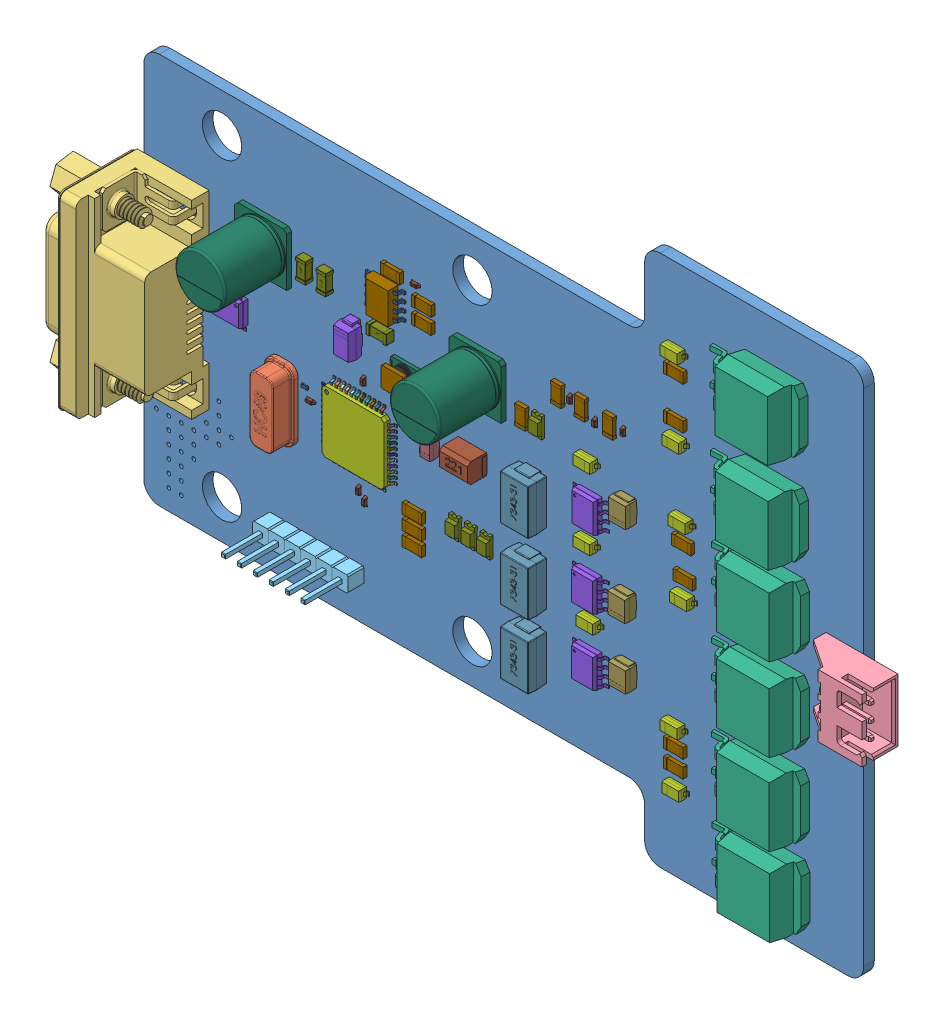
SolidWorks assembly PCB_BLDC421232_СБ, configuration По умолчанию. Lengths in mm.
Overall size (126.59 85 25.25).
246 component instances, 91 part files, 0 mates.
Components (placement in the parent):
- Board-1: Board [По умолчанию] at origin size (115 85 1.69)
- ZQ1-1: ZQ1 [По умолчанию] at origin size (4.65 11.35 16.3)
  - User_Library-HC49_Crystal-1: User_Library-HC49_Crystal [По умолчанию] at (22.338 -6.587 0) x (0 1 0) z (1 0 0) size (11.35 16.3 4.65)
- XS1-1: XS1 [По умолчанию] at origin size (16.7 30.5 16.4)
  - User_Library-DB-9F-1: User_Library-DB-9F [По умолчанию] at (-1.1101 1.395 6.3) x (0 -1 0) z (-1 0 0) size (30.5 16.4 16.7)
- XP2-1: XP2 [По умолчанию] at origin size (11.5 10 9.25)
  - User_Library-DS1069-3_CWF-3R-1: User_Library-DS1069-3_CWF-3R [По умолчанию] at (111.5999 -2.9999 0) x (0 1 0) z (0 0 1) size (10 11.5 9.25)
- XP1-1: XP1 [По умолчанию] at origin size (15.24 2.54 11.54)
  - User_Library-PLS-2-1: User_Library-PLS-2 [По умолчанию] at (19.9299 -25.8001 0) x (1 0 0) z (0 -1 0) size (5.08 11.54 2.54)
  - User_Library-PLS-2-2: User_Library-PLS-2 [По умолчанию] at (25.0099 -25.8001 0) x (1 0 0) z (0 -1 0) size (5.08 11.54 2.54)
  - User_Library-PLS-2-3: User_Library-PLS-2 [По умолчанию] at (30.0899 -25.8001 0) x (1 0 0) z (0 -1 0) size (5.08 11.54 2.54)
- VT6-1: VT6 [По умолчанию] at origin size (15.26 10.16 5.02)
  - SW3dPS-DPAK-1: SW3dPS-DPAK [По умолчанию] at (100.6751 -33.2751 2.5) x (0 -1 0) z (-1 0 0) size (10.16 5.02 15.26)
- VT5-1: VT5 [По умолчанию] at origin size (15.26 10.16 5.02)
  - SW3dPS-DPAK-1: SW3dPS-DPAK [По умолчанию] at (100.5951 -20.7351 2.5) x (0 -1 0) z (-1 0 0) size (10.16 5.02 15.26)
- VT4-1: VT4 [По умолчанию] at origin size (15.26 10.16 5.02)
  - SW3dPS-DPAK-1: SW3dPS-DPAK [По умолчанию] at (100.5951 -7.7351 2.5) x (0 -1 0) z (-1 0 0) size (10.16 5.02 15.26)
- VT3-1: VT3 [По умолчанию] at origin size (15.26 10.16 5.02)
  - SW3dPS-DPAK-1: SW3dPS-DPAK [По умолчанию] at (100.5951 5.5149 2.5) x (0 -1 0) z (-1 0 0) size (10.16 5.02 15.26)
- VT2-1: VT2 [По умолчанию] at origin size (15.26 10.16 5.02)
  - SW3dPS-DPAK-1: SW3dPS-DPAK [По умолчанию] at (100.4251 18.1019 2.5) x (0 -1 0) z (-1 0 0) size (10.16 5.02 15.26)
- VT1-1: VT1 [По умолчанию] at origin size (15.26 10.16 5.02)
  - SW3dPS-DPAK-1: SW3dPS-DPAK [По умолчанию] at (100.3451 32.5619 2.5) x (0 -1 0) z (-1 0 0) size (10.16 5.02 15.26)
- VD10-1: VD10 [По умолчанию] at origin size (3.7 1.6 1.27)
  - SW3DPS-SOD123-DEFAULT-1: SW3DPS-SOD123-DEFAULT [По умолчанию] at (85.3569 -28.75 0) x (-1 0 0) z (0 1 0) size (3.7 1.27 1.6)
- VD9-1: VD9 [По умолчанию] at origin size (3.7 1.6 1.27)
  - SW3DPS-SOD123-DEFAULT-1: SW3DPS-SOD123-DEFAULT [По умолчанию] at (85.1069 -20.25 0) x (-1 0 0) z (0 1 0) size (3.7 1.27 1.6)
- VD8-1: VD8 [По умолчанию] at origin size (3.7 1.6 1.27)
  - SW3DPS-SOD123-DEFAULT-1: SW3DPS-SOD123-DEFAULT [По умолчанию] at (86.6069 -1.75 0) x (-1 0 0) z (0 1 0) size (3.7 1.27 1.6)
- VD7-1: VD7 [По умолчанию] at origin size (3.7 1.6 1.27)
  - SW3DPS-SOD123-DEFAULT-1: SW3DPS-SOD123-DEFAULT [По умолчанию] at (86.3569 8.75 0) x (-1 0 0) z (0 1 0) size (3.7 1.27 1.6)
- VD6-1: VD6 [По умолчанию] at origin size (3.7 1.6 1.27)
  - SW3DPS-SOD123-DEFAULT-1: SW3DPS-SOD123-DEFAULT [По умолчанию] at (85.3649 19.377 0) x (-1 0 0) z (0 1 0) size (3.7 1.27 1.6)
- VD5-1: VD5 [По умолчанию] at origin size (3.7 1.6 1.27)
  - SW3DPS-SOD123-DEFAULT-1: SW3DPS-SOD123-DEFAULT [По умолчанию] at (85.1069 31.6269 0) x (-1 0 0) z (0 1 0) size (3.7 1.27 1.6)
- VD4-1: VD4 [По умолчанию] at origin size (3.7 1.6 1.27)
  - SW3DPS-SOD123-DEFAULT-1: SW3DPS-SOD123-DEFAULT [По умолчанию] at (71.6431 -12.5 0) x (1 0 0) z (0 -1 0) size (3.7 1.27 1.6)
- VD3-1: VD3 [По умолчанию] at origin size (3.7 1.6 1.27)
  - SW3DPS-SOD123-DEFAULT-1: SW3DPS-SOD123-DEFAULT [По умолчанию] at (71.1431 -1.75 0) x (1 0 0) z (0 -1 0) size (3.7 1.27 1.6)
- VD2-1: VD2 [По умолчанию] at origin size (3.7 1.6 1.27)
  - SW3DPS-SOD123-DEFAULT-1: SW3DPS-SOD123-DEFAULT [По умолчанию] at (71.1431 9.5 0) x (1 0 0) z (0 -1 0) size (3.7 1.27 1.6)
- VD1-1: VD1 [По умолчанию] at origin size (2.6 5.21 2.43)
  - SW3dPS-DO-214AC_SMA-1: SW3dPS-DO-214AC_SMA [По умолчанию] at (33.9999 8.2001 1.5) x (1 0 0) z (0 0 1) size (2.6 5.21 2.43)
- R24-1: R24 [По умолчанию] at origin size (1.66 3.1 0.62)
  - ЁхчшёЄюЁ-1206-1: ЁхчшёЄюЁ-1206 [По умолчанию] at (60.7501 10.4999 0.09) x (0 -1 0) z (-1 0 0) size (3.1 0.62 1.66)
- R23-1: R23 [По умолчанию] at origin size (3.1 1.66 0.62)
  - ЁхчшёЄюЁ-1206-1: ЁхчшёЄюЁ-1206 [По умолчанию] at (85.2501 -25.7499 0.09) x (1 0 0) z (0 -1 0) size (3.1 0.62 1.66)
- R22-1: R22 [По умолчанию] at origin size (3.1 1.66 0.62)
  - ЁхчшёЄюЁ-1206-1: ЁхчшёЄюЁ-1206 [По умолчанию] at (85.2501 -22.9999 0.09) x (1 0 0) z (0 -1 0) size (3.1 0.62 1.66)
- R21-1: R21 [По умолчанию] at origin size (3.1 1.66 0.62)
  - ЁхчшёЄюЁ-1206-1: ЁхчшёЄюЁ-1206 [По умолчанию] at (86.7501 1.0001 0.09) x (1 0 0) z (0 -1 0) size (3.1 0.62 1.66)
- R20-1: R20 [По умолчанию] at origin size (3.1 1.66 0.62)
  - ЁхчшёЄюЁ-1206-1: ЁхчшёЄюЁ-1206 [По умолчанию] at (86.5001 5.7501 0.09) x (1 0 0) z (0 -1 0) size (3.1 0.62 1.66)
- R19-1: R19 [По умолчанию] at origin size (3.1 1.66 0.62)
  - ЁхчшёЄюЁ-1206-1: ЁхчшёЄюЁ-1206 [По умолчанию] at (85.2501 22.1271 0.09) x (1 0 0) z (0 -1 0) size (3.1 0.62 1.66)
- R18-1: R18 [По умолчанию] at origin size (3.1 1.66 0.62)
  - ЁхчшёЄюЁ-1206-1: ЁхчшёЄюЁ-1206 [По умолчанию] at (85.2501 28.8771 0.09) x (1 0 0) z (0 -1 0) size (3.1 0.62 1.66)
- R17-1: R17 [По умолчанию] at origin size (1 0.5 0.25)
  - User_Library-d0402h025-1: User_Library-d0402h025 [По умолчанию] at (52.6499 -1.9999 0) x (-1 0 0) z (0 0 1) size (1 0.5 0.25)
- R16-1: R16 [По умолчанию] at origin size (3.1 1.66 0.62)
  - ЁхчшёЄюЁ-1206-1: ЁхчшёЄюЁ-1206 [По умолчанию] at (73.7501 20.9999 -1.7814) x (1 0 0) z (0 1 0) size (3.1 0.62 1.66)
- R15-1: R15 [По умолчанию] at origin size (3.1 1.66 0.62)
  - ЁхчшёЄюЁ-1206-1: ЁхчшёЄюЁ-1206 [По умолчанию] at (73.7501 23.7499 -1.7814) x (1 0 0) z (0 1 0) size (3.1 0.62 1.66)
- R14-1: R14 [По умолчанию] at origin size (3.1 1.66 0.62)
  - ЁхчшёЄюЁ-1206-1: ЁхчшёЄюЁ-1206 [По умолчанию] at (73.7501 26.2499 -1.7814) x (1 0 0) z (0 1 0) size (3.1 0.62 1.66)
- R13-1: R13 [По умолчанию] at origin size (1.66 3.1 0.62)
  - ЁхчшёЄюЁ-1206-1: ЁхчшёЄюЁ-1206 [По умолчанию] at (74.7499 16.2501 0.09) x (0 1 0) z (1 0 0) size (3.1 0.62 1.66)
- R12-1: R12 [По умолчанию] at origin size (1.66 3.1 0.62)
  - ЁхчшёЄюЁ-1206-1: ЁхчшёЄюЁ-1206 [По умолчанию] at (70.2499 16.5001 0.09) x (0 1 0) z (1 0 0) size (3.1 0.62 1.66)
- R11-1: R11 [По умолчанию] at origin size (3.1 1.66 0.62)
  - ЁхчшёЄюЁ-1206-1: ЁхчшёЄюЁ-1206 [По умолчанию] at (67.0001 20.9999 -1.7814) x (1 0 0) z (0 1 0) size (3.1 0.62 1.66)
- R10-1: R10 [По умолчанию] at origin size (3.1 1.66 0.62)
  - ЁхчшёЄюЁ-1206-1: ЁхчшёЄюЁ-1206 [По умолчанию] at (67.0001 23.7499 -1.7814) x (1 0 0) z (0 1 0) size (3.1 0.62 1.66)
- R9-1: R9 [По умолчанию] at origin size (3.1 1.66 0.62)
  - ЁхчшёЄюЁ-1206-1: ЁхчшёЄюЁ-1206 [По умолчанию] at (67.0001 26.2499 -1.7814) x (1 0 0) z (0 1 0) size (3.1 0.62 1.66)
- R8-1: R8 [По умолчанию] at origin size (1.66 3.1 0.62)
  - ЁхчшёЄюЁ-1206-1: ЁхчшёЄюЁ-1206 [По умолчанию] at (66.4999 16.5001 0.09) x (0 1 0) z (1 0 0) size (3.1 0.62 1.66)
- R7-1: R7 [По умолчанию] at origin size (1 0.5 0.25)
  - User_Library-d0402h025-1: User_Library-d0402h025 [По умолчанию] at (25.8501 -3.0001 0) x (1 0 0) z (0 0 1) size (1 0.5 0.25)
- R6-1: R6 [По умолчанию] at origin size (3.1 1.66 0.62)
  - ЁхчшёЄюЁ-1206-1: ЁхчшёЄюЁ-1206 [По умолчанию] at (45.0001 15.5001 0.09) x (1 0 0) z (0 -1 0) size (3.1 0.62 1.66)
- R5-1: R5 [По умолчанию] at origin size (3.1 1.66 0.62)
  - ЁхчшёЄюЁ-1206-1: ЁхчшёЄюЁ-1206 [По умолчанию] at (45.0001 18.0001 0.09) x (1 0 0) z (0 -1 0) size (3.1 0.62 1.66)
- R4-1: R4 [По умолчанию] at origin size (3.1 1.66 0.62)
  - ЁхчшёЄюЁ-1206-1: ЁхчшёЄюЁ-1206 [По умолчанию] at (40.0001 20.0001 0.09) x (1 0 0) z (0 -1 0) size (3.1 0.62 1.66)
- R3-1: R3 [По умолчанию] at origin size (3.1 1.66 0.62)
  - ЁхчшёЄюЁ-1206-1: ЁхчшёЄюЁ-1206 [По умолчанию] at (43.4999 -16.0001 0.09) x (-1 0 0) z (0 1 0) size (3.1 0.62 1.66)
- R2-1: R2 [По умолчанию] at origin size (3.1 1.66 0.62)
  - ЁхчшёЄюЁ-1206-1: ЁхчшёЄюЁ-1206 [По умолчанию] at (43.4999 -11.5001 0.09) x (-1 0 0) z (0 1 0) size (3.1 0.62 1.66)
- R1-1: R1 [По умолчанию] at origin size (3.1 1.66 0.62)
  - ЁхчшёЄюЁ-1206-1: ЁхчшёЄюЁ-1206 [По умолчанию] at (43.4999 -13.7501 0.09) x (-1 0 0) z (0 1 0) size (3.1 0.62 1.66)
- L2-1: L2 [По умолчанию] at origin size (4.65 3.2 3.08)
  - ╚эфєъЄштэюёЄ№NLC453232-1: ╚эфєъЄштэюёЄ№NLC453232 [По умолчанию] at (52.5359 0.699 0.05) x (1 0 0) z (0 -1 0) size (4.65 3.08 3.2)
- L1-1: L1 [По умолчанию] at origin size (4.6 3.2 2.6)
  - User_Library-lqh4c_1812-1: User_Library-lqh4c_1812 [По умолчанию] at (42.25 7 0) x (1 0 0) z (0 0 1) size (4.6 3.2 2.6)
    - User_Library-lqh4c_1812_Torus-1: User_Library-lqh4c_1812_Torus [По умолчанию] at origin size (2.9 2.9 0.1)
    - User_Library-lqh4c_1812_Torus001-1: User_Library-lqh4c_1812_Torus001 [По умолчанию] at origin size (2.9 2.9 0.1)
    - User_Library-lqh4c_1812_Torus002-1: User_Library-lqh4c_1812_Torus002 [По умолчанию] at origin size (2.9 2.9 0.1)
    - User_Library-lqh4c_1812_Torus003-1: User_Library-lqh4c_1812_Torus003 [По умолчанию] at origin size (2.9 2.9 0.1)
    - User_Library-lqh4c_1812_Torus004-1: User_Library-lqh4c_1812_Torus004 [По умолчанию] at origin size (2.9 2.9 0.1)
    - User_Library-lqh4c_1812_Torus005-1: User_Library-lqh4c_1812_Torus005 [По умолчанию] at origin size (2.9 2.9 0.1)
    - User_Library-lqh4c_1812_Torus006-1: User_Library-lqh4c_1812_Torus006 [По умолчанию] at origin size (2.9 2.9 0.1)
    - User_Library-lqh4c_1812_Torus007-1: User_Library-lqh4c_1812_Torus007 [По умолчанию] at origin size (2.9 2.9 0.1)
    - User_Library-lqh4c_1812_Torus008-1: User_Library-lqh4c_1812_Torus008 [По умолчанию] at origin size (2.9 2.9 0.1)
    - User_Library-lqh4c_1812_Torus009-1: User_Library-lqh4c_1812_Torus009 [По умолчанию] at origin size (2.9 2.9 0.1)
    - User_Library-lqh4c_1812_Torus010-1: User_Library-lqh4c_1812_Torus010 [По умолчанию] at origin size (2.9 2.9 0.1)
    - User_Library-lqh4c_1812_Torus011-1: User_Library-lqh4c_1812_Torus011 [По умолчанию] at origin size (2.9 2.9 0.1)
    - User_Library-lqh4c_1812_Torus012-1: User_Library-lqh4c_1812_Torus012 [По умолчанию] at origin size (2.9 2.9 0.1)
    - User_Library-lqh4c_1812_Torus013-1: User_Library-lqh4c_1812_Torus013 [По умолчанию] at origin size (2.9 2.9 0.1)
    - User_Library-lqh4c_1812_Torus014-1: User_Library-lqh4c_1812_Torus014 [По умолчанию] at origin size (2.9 2.9 0.1)
    - User_Library-lqh4c_1812_Fillet001-1: User_Library-lqh4c_1812_Fillet001 [По умолчанию] at origin size (3.5 3.2 0.6)
    - User_Library-lqh4c_1812_Cube002-1: User_Library-lqh4c_1812_Cube002 [По умолчанию] at origin size (0.3 2.2 0.65)
    - User_Library-lqh4c_1812_Cube003-1: User_Library-lqh4c_1812_Cube003 [По умолчанию] at origin size (0.3 2.2 0.65)
    - User_Library-lqh4c_1812_Cube004-1: User_Library-lqh4c_1812_Cube004 [По умолчанию] at origin size (1 2.2 0.3)
    - User_Library-lqh4c_1812_Cube005-1: User_Library-lqh4c_1812_Cube005 [По умолчанию] at origin size (1 2.2 0.3)
    - User_Library-lqh4c_1812_Cylinder002-1: User_Library-lqh4c_1812_Cylinder002 [По умолчанию] at origin
    - User_Library-lqh4c_1812_Cylinder003-1: User_Library-lqh4c_1812_Cylinder003 [По умолчанию] at origin
    - User_Library-lqh4c_1812_Cylinder004-1: User_Library-lqh4c_1812_Cylinder004 [По умолчанию] at origin
    - User_Library-lqh4c_1812_Fillet002-1: User_Library-lqh4c_1812_Fillet002 [По умолчанию] at origin size (0.09 0.09 0.1)
    - User_Library-lqh4c_1812_Cut002-1: User_Library-lqh4c_1812_Cut002 [По умолчанию] at origin size (4.5 3.2 0.53)
- HL4-1: HL4 [По умолчанию] at origin size (1.6 3.2 1.1)
  - CircuitWorks-LED_1206-1: CircuitWorks-LED_1206 [По умолчанию] at (63.2501 10.4999 0) x (1 0 0) z (0 -1 0) size (1.6 1.1 3.2)
- HL3-1: HL3 [По умолчанию] at origin size (1.6 3.2 1.1)
  - CircuitWorks-LED_1206-1: CircuitWorks-LED_1206 [По умолчанию] at (54.9999 -10.2499 0) x (-1 0 0) z (0 1 0) size (1.6 1.1 3.2)
- HL2-1: HL2 [По умолчанию] at origin size (1.6 3.2 1.1)
  - CircuitWorks-LED_1206-1: CircuitWorks-LED_1206 [По умолчанию] at (52.4999 -10.2499 0) x (-1 0 0) z (0 1 0) size (1.6 1.1 3.2)
- HL1-1: HL1 [По умолчанию] at origin size (1.6 3.2 1.1)
  - CircuitWorks-LED_1206-1: CircuitWorks-LED_1206 [По умолчанию] at (49.9999 -10.2499 0) x (-1 0 0) z (0 1 0) size (1.6 1.1 3.2)
- DD2-1: DD2 [По умолчанию] at origin size (12 12 1.1)
  - User_Library-TQFP-44-1-1: User_Library-TQFP-44-1 [По умолчанию] at (28.4999 0.7811 0) x (0 -1 0) z (0 0 1) size (12 12 1.1)
    - User_Library-TQFP-44-1_pin001-1: User_Library-TQFP-44-1_pin001 [По умолчанию] at origin size (0.36 1 0.6)
    - User_Library-TQFP-44-1_pin021-1: User_Library-TQFP-44-1_pin021 [По умолчанию] at origin size (1 0.36 0.6)
    - User_Library-TQFP-44-1_pin022-1: User_Library-TQFP-44-1_pin022 [По умолчанию] at origin size (1 0.36 0.6)
    - User_Library-TQFP-44-1_pin020-1: User_Library-TQFP-44-1_pin020 [По умолчанию] at origin size (1 0.36 0.6)
    - User_Library-TQFP-44-1_pin019-1: User_Library-TQFP-44-1_pin019 [По умолчанию] at origin size (1 0.36 0.6)
    - User_Library-TQFP-44-1_pin018-1: User_Library-TQFP-44-1_pin018 [По умолчанию] at origin size (1 0.36 0.6)
    - User_Library-TQFP-44-1_pin017-1: User_Library-TQFP-44-1_pin017 [По умолчанию] at origin size (1 0.36 0.6)
    - User_Library-TQFP-44-1_pin024-1: User_Library-TQFP-44-1_pin024 [По умолчанию] at origin size (0.36 1 0.6)
    - User_Library-TQFP-44-1_pin023-1: User_Library-TQFP-44-1_pin023 [По умолчанию] at origin size (0.36 1 0.6)
    - User_Library-TQFP-44-1_pin007-1: User_Library-TQFP-44-1_pin007 [По умолчанию] at origin size (0.36 1 0.6)
    - User_Library-TQFP-44-1_pin003-1: User_Library-TQFP-44-1_pin003 [По умолчанию] at origin size (0.36 1 0.6)
    - User_Library-TQFP-44-1_pin015-1: User_Library-TQFP-44-1_pin015 [По умолчанию] at origin size (1 0.36 0.6)
    - User_Library-TQFP-44-1_pin014-1: User_Library-TQFP-44-1_pin014 [По умолчанию] at origin size (1 0.36 0.6)
    - User_Library-TQFP-44-1_pin013-1: User_Library-TQFP-44-1_pin013 [По умолчанию] at origin size (1 0.36 0.6)
    - User_Library-TQFP-44-1_pin012-1: User_Library-TQFP-44-1_pin012 [По умолчанию] at origin size (1 0.36 0.6)
    - User_Library-TQFP-44-1_pin011-1: User_Library-TQFP-44-1_pin011 [По умолчанию] at origin size (0.36 1 0.6)
    - User_Library-TQFP-44-1_pin010-1: User_Library-TQFP-44-1_pin010 [По умолчанию] at origin size (0.36 1 0.6)
    - User_Library-TQFP-44-1_pin009-1: User_Library-TQFP-44-1_pin009 [По умолчанию] at origin size (0.36 1 0.6)
    - User_Library-TQFP-44-1_pin008-1: User_Library-TQFP-44-1_pin008 [По умолчанию] at origin size (0.36 1 0.6)
    - User_Library-TQFP-44-1_pin006-1: User_Library-TQFP-44-1_pin006 [По умолчанию] at origin size (0.36 1 0.6)
    - User_Library-TQFP-44-1_pin005-1: User_Library-TQFP-44-1_pin005 [По умолчанию] at origin size (0.36 1 0.6)
    - User_Library-TQFP-44-1_pin004-1: User_Library-TQFP-44-1_pin004 [По умолчанию] at origin size (0.36 1 0.6)
    - User_Library-TQFP-44-1_pin002-1: User_Library-TQFP-44-1_pin002 [По умолчанию] at origin size (0.36 1 0.6)
    - User_Library-TQFP-44-1_pin016-1: User_Library-TQFP-44-1_pin016 [По умолчанию] at origin size (1 0.36 0.6)
    - User_Library-TQFP-44-1_pin027-1: User_Library-TQFP-44-1_pin027 [По умолчанию] at origin size (0.36 1 0.6)
    - User_Library-TQFP-44-1_pin037-1: User_Library-TQFP-44-1_pin037 [По умолчанию] at origin size (1 0.36 0.6)
    - User_Library-TQFP-44-1_pin025-1: User_Library-TQFP-44-1_pin025 [По умолчанию] at origin size (0.36 1 0.6)
    - User_Library-TQFP-44-1_pin026-1: User_Library-TQFP-44-1_pin026 [По умолчанию] at origin size (0.36 1 0.6)
    - User_Library-TQFP-44-1_pin036-1: User_Library-TQFP-44-1_pin036 [По умолчанию] at origin size (1 0.36 0.6)
    - User_Library-TQFP-44-1_pin035-1: User_Library-TQFP-44-1_pin035 [По умолчанию] at origin size (1 0.36 0.6)
    - User_Library-TQFP-44-1_pin034-1: User_Library-TQFP-44-1_pin034 [По умолчанию] at origin size (1 0.36 0.6)
    - User_Library-TQFP-44-1_pin033-1: User_Library-TQFP-44-1_pin033 [По умолчанию] at origin size (0.36 1 0.6)
    - User_Library-TQFP-44-1_pin032-1: User_Library-TQFP-44-1_pin032 [По умолчанию] at origin size (0.36 1 0.6)
    - User_Library-TQFP-44-1_pin031-1: User_Library-TQFP-44-1_pin031 [По умолчанию] at origin size (0.36 1 0.6)
    - User_Library-TQFP-44-1_pin030-1: User_Library-TQFP-44-1_pin030 [По умолчанию] at origin size (0.36 1 0.6)
    - User_Library-TQFP-44-1_pin029-1: User_Library-TQFP-44-1_pin029 [По умолчанию] at origin size (0.36 1 0.6)
    - User_Library-TQFP-44-1_pin028-1: User_Library-TQFP-44-1_pin028 [По умолчанию] at origin size (0.36 1 0.6)
    - User_Library-TQFP-44-1_pin038-1: User_Library-TQFP-44-1_pin038 [По умолчанию] at origin size (1 0.36 0.6)
    - User_Library-TQFP-44-1_pin044-1: User_Library-TQFP-44-1_pin044 [По умолчанию] at origin size (1 0.36 0.6)
    - User_Library-TQFP-44-1_pin043-1: User_Library-TQFP-44-1_pin043 [По умолчанию] at origin size (1 0.36 0.6)
    - User_Library-TQFP-44-1_pin042-1: User_Library-TQFP-44-1_pin042 [По умолчанию] at origin size (1 0.36 0.6)
    - User_Library-TQFP-44-1_pin041-1: User_Library-TQFP-44-1_pin041 [По умолчанию] at origin size (1 0.36 0.6)
    - User_Library-TQFP-44-1_pin040-1: User_Library-TQFP-44-1_pin040 [По умолчанию] at origin size (1 0.36 0.6)
    - User_Library-TQFP-44-1_pin039-1: User_Library-TQFP-44-1_pin039 [По умолчанию] at origin size (1 0.36 0.6)
    - User_Library-TQFP-44-1_Body-1: User_Library-TQFP-44-1_Body [По умолчанию] at origin size (10 10 1)
- DD1-1: DD1 [По умолчанию] at origin size (4.9 5.78 1.45)
  - SW3DPS-SO-8-DEFAULT-1: SW3DPS-SO-8-DEFAULT [По умолчанию] at (16.2391 5.397 0) x (0 -1 0) z (-1 0 0) size (5.78 1.45 4.9)
- DA4-1: DA4 [По умолчанию] at origin size (5.78 4.9 1.45)
  - SW3DPS-SO-8-DEFAULT-1: SW3DPS-SO-8-DEFAULT [По умолчанию] at (68.8529 -16.5509 0) x (1 0 0) z (0 -1 0) size (5.78 1.45 4.9)
- DA3-1: DA3 [По умолчанию] at origin size (5.78 4.9 1.45)
  - SW3DPS-SO-8-DEFAULT-1: SW3DPS-SO-8-DEFAULT [По умолчанию] at (68.853 -5.9909 0) x (1 0 0) z (0 -1 0) size (5.78 1.45 4.9)
- DA2-1: DA2 [По умолчанию] at origin size (5.78 4.9 1.45)
  - SW3DPS-SO-8-DEFAULT-1: SW3DPS-SO-8-DEFAULT [По умолчанию] at (68.903 4.9491 0) x (1 0 0) z (0 -1 0) size (5.78 1.45 4.9)
- DA1-1: DA1 [По умолчанию] at origin size (6.2 5 1.75)
  - User_Library-HSOP8-1: User_Library-HSOP8 [По умолчанию] at (38.75 16 0) x (-1 0 0) z (0 1 0) size (6.2 1.75 5)
    - User_Library-HSOP8_part_hsop8_____________-1: User_Library-HSOP8_part_hsop8_____________ [По умолчанию] at origin size (4 1.75 5)
    - User_Library-HSOP8_Assy_fuss_hsop8_____________-1: User_Library-HSOP8_Assy_fuss_hsop8_____________ [По умолчанию] at (2 0 0) size (1.1 0.95 4.25)
      - User_Library-HSOP8_Fuss_hsop8_____________-1: User_Library-HSOP8_Fuss_hsop8_____________ [По умолчанию] at (0 0 -0.635) size (1.1 0.95 0.44)
      - User_Library-HSOP8_Fuss_hsop8_____________-2: User_Library-HSOP8_Fuss_hsop8_____________ [По умолчанию] at (0 0 0.635) size (1.1 0.95 0.44)
      - User_Library-HSOP8_Fuss_hsop8_____________-3: User_Library-HSOP8_Fuss_hsop8_____________ [По умолчанию] at (0 0 1.905) size (1.1 0.95 0.44)
      - User_Library-HSOP8_Fuss_hsop8_____________-4: User_Library-HSOP8_Fuss_hsop8_____________ [По умолчанию] at (0 0 -1.905) size (1.1 0.95 0.44)
      - User_Library-HSOP8_Fuss_hsop8_____________-5: User_Library-HSOP8_Fuss_hsop8_____________ [По умолчанию] at (0 0 -0.635) size (1.1 0.95 0.44)
      - User_Library-HSOP8_Fuss_hsop8_____________-6: User_Library-HSOP8_Fuss_hsop8_____________ [По умолчанию] at (0 0 0.635) size (1.1 0.95 0.44)
    - User_Library-HSOP8_Assy_fuss_hsop8_____________-2: User_Library-HSOP8_Assy_fuss_hsop8_____________ [По умолчанию] at (-2 0 0) x (-1 0 0) z (0 0 -1) size (1.1 0.95 4.25)
      - User_Library-HSOP8_Fuss_hsop8_____________-1: User_Library-HSOP8_Fuss_hsop8_____________ [По умолчанию] at (0 0 -0.635) size (1.1 0.95 0.44)
      - User_Library-HSOP8_Fuss_hsop8_____________-2: User_Library-HSOP8_Fuss_hsop8_____________ [По умолчанию] at (0 0 0.635) size (1.1 0.95 0.44)
      - User_Library-HSOP8_Fuss_hsop8_____________-3: User_Library-HSOP8_Fuss_hsop8_____________ [По умолчанию] at (0 0 1.905) size (1.1 0.95 0.44)
      - User_Library-HSOP8_Fuss_hsop8_____________-4: User_Library-HSOP8_Fuss_hsop8_____________ [По умолчанию] at (0 0 -1.905) size (1.1 0.95 0.44)
      - User_Library-HSOP8_Fuss_hsop8_____________-5: User_Library-HSOP8_Fuss_hsop8_____________ [По умолчанию] at (0 0 -0.635) size (1.1 0.95 0.44)
      - User_Library-HSOP8_Fuss_hsop8_____________-6: User_Library-HSOP8_Fuss_hsop8_____________ [По умолчанию] at (0 0 0.635) size (1.1 0.95 0.44)
- C23-1: C23 [По умолчанию] at origin size (0.56 1.48 0.53)
  - User_Library-User_Library-0402_Cap-1: User_Library-User_Library-0402_Cap [По умолчанию] at (35.4789 -14.0749 0) x (0 -1 0) z (0 0 1) size (1.48 0.56 0.53)
- C22-1: C22 [По умолчанию] at origin size (0.56 1.48 0.53)
  - User_Library-User_Library-0402_Cap-1: User_Library-User_Library-0402_Cap [По умолчанию] at (35.2539 2.5001 0) x (0 -1 0) z (0 0 1) size (1.48 0.56 0.53)
- C21-1: C21 [По умолчанию] at origin size (0.56 1.48 0.53)
  - User_Library-User_Library-0402_Cap-1: User_Library-User_Library-0402_Cap [По умолчанию] at (34.4961 -13.0001 0) x (0 1 0) z (0 0 1) size (1.48 0.56 0.53)
- C20-1: C20 [По умолчанию] at origin size (1.48 0.56 0.53)
  - User_Library-User_Library-0402_Cap-1: User_Library-User_Library-0402_Cap [По умолчанию] at (26.7499 -4.4961 0) x (1 0 0) z (0 0 1) size (1.48 0.56 0.53)
- C19-1: C19 [По умолчанию] at origin size (2.8 3.49 1.91)
  - User_Library-cap_b-1: User_Library-cap_b [По умолчанию] at (77.4751 -16.5751 0) x (0 1 0) z (1 0 0) size (3.49 1.91 2.8)
- C18-1: C18 [По умолчанию] at origin size (2.8 3.49 1.91)
  - User_Library-cap_b-1: User_Library-cap_b [По умолчанию] at (77.3751 -6.8751 0) x (0 1 0) z (1 0 0) size (3.49 1.91 2.8)
- C17-1: C17 [По умолчанию] at origin size (2.8 3.49 1.91)
  - User_Library-cap_b-1: User_Library-cap_b [По умолчанию] at (77.4751 6.1749 0) x (0 1 0) z (1 0 0) size (3.49 1.91 2.8)
- C16-1: C16 [По умолчанию] at origin size (0.56 1.48 0.53)
  - User_Library-User_Library-0402_Cap-1: User_Library-User_Library-0402_Cap [По умолчанию] at (44.7461 -2.2501 0) x (0 1 0) z (0 0 1) size (1.48 0.56 0.53)
- C15-1: C15 [По умолчанию] at origin size (1.6 3.19 1.61)
  - SW3dPS-cap_a-1: SW3dPS-cap_a [По умолчанию] at (46.4999 -0.4999 0) x (0 1 0) z (1 0 0) size (3.19 1.61 1.6)
- C14-1: C14 [По умолчанию] at origin size (4.6 7.6 3.1)
  - User_Library-CAP_TANT_7343-31-1: User_Library-CAP_TANT_7343-31 [По умолчанию] at (62.2641 -21.1981 0) x (0 1 0) z (1 0 0) size (7.6 3.1 4.6)
- C13-1: C13 [По умолчанию] at origin size (4.6 7.6 3.1)
  - User_Library-CAP_TANT_7343-31-1: User_Library-CAP_TANT_7343-31 [По умолчанию] at (62.2641 -10.9481 0) x (0 1 0) z (1 0 0) size (7.6 3.1 4.6)
- C12-1: C12 [По умолчанию] at origin size (4.6 7.6 3.1)
  - User_Library-CAP_TANT_7343-31-1: User_Library-CAP_TANT_7343-31 [По умолчанию] at (62.2641 0.3209 0) x (0 1 0) z (1 0 0) size (7.6 3.1 4.6)
- C11-1: C11 [По умолчанию] at origin size (0.56 1.48 0.53)
  - User_Library-User_Library-0402_Cap-1: User_Library-User_Library-0402_Cap [По умолчанию] at (76.7461 16.2499 0) x (0 1 0) z (0 0 1) size (1.48 0.56 0.53)
- C10-1: C10 [По умолчанию] at origin size (0.56 1.48 0.53)
  - User_Library-User_Library-0402_Cap-1: User_Library-User_Library-0402_Cap [По умолчанию] at (18.9961 -4.6751 0) x (0 1 0) z (0 0 1) size (1.48 0.56 0.53)
- C9-1: C9 [По умолчанию] at origin size (0.56 1.48 0.53)
  - User_Library-User_Library-0402_Cap-1: User_Library-User_Library-0402_Cap [По умолчанию] at (72.2461 15.2499 0) x (0 1 0) z (0 0 1) size (1.48 0.56 0.53)
- C8-1: C8 [По умолчанию] at origin size (0.56 1.48 0.53)
  - User_Library-User_Library-0402_Cap-1: User_Library-User_Library-0402_Cap [По умолчанию] at (19.0039 -8.4499 0) x (0 -1 0) z (0 0 1) size (1.48 0.56 0.53)
- C7-1: C7 [По умолчанию] at origin size (0.56 1.48 0.53)
  - User_Library-User_Library-0402_Cap-1: User_Library-User_Library-0402_Cap [По умолчанию] at (68.2461 16.4999 0) x (0 1 0) z (0 0 1) size (1.48 0.56 0.53)
- C6-1: C6 [По умолчанию] at origin size (8.3 8.3 10.55)
  - User_Library-capasitores_electroliticos-1: User_Library-capasitores_electroliticos [По умолчанию] at (53.7251 12.3999 0) x (0 -1 0) z (0 0 -1) size (8.3 8.3 10.55)
- C5-1: C5 [По умолчанию] at origin size (1.48 0.56 0.53)
  - User_Library-User_Library-0402_Cap-1: User_Library-User_Library-0402_Cap [По умолчанию] at (43.4999 20.0039 0) x (1 0 0) z (0 0 1) size (1.48 0.56 0.53)
- C4-1: C4 [По умолчанию] at origin size (3.2 1.6 1.35)
  - User_Library-capc3216L-1: User_Library-capc3216L [По умолчанию] at (38.3501 11.0251 0) x (1 0 0) z (0 -1 0) size (3.2 1.35 1.6)
- C3-1: C3 [По умолчанию] at origin size (1.6 3.2 1.35)
  - User_Library-capc3216L-1: User_Library-capc3216L [По умолчанию] at (26.2499 13.7501 0) x (0 1 0) z (1 0 0) size (3.2 1.35 1.6)
- C2-1: C2 [По умолчанию] at origin size (1.6 3.2 1.35)
  - User_Library-capc3216L-1: User_Library-capc3216L [По умолчанию] at (29.4999 13.7501 0) x (0 1 0) z (1 0 0) size (3.2 1.35 1.6)
- C1-1: C1 [По умолчанию] at origin size (8.3 8.3 10.55)
  - User_Library-capasitores_electroliticos-1: User_Library-capasitores_electroliticos [По умолчанию] at (19.4751 13.6499 0) x (0 -1 0) z (0 0 -1) size (8.3 8.3 10.55)
